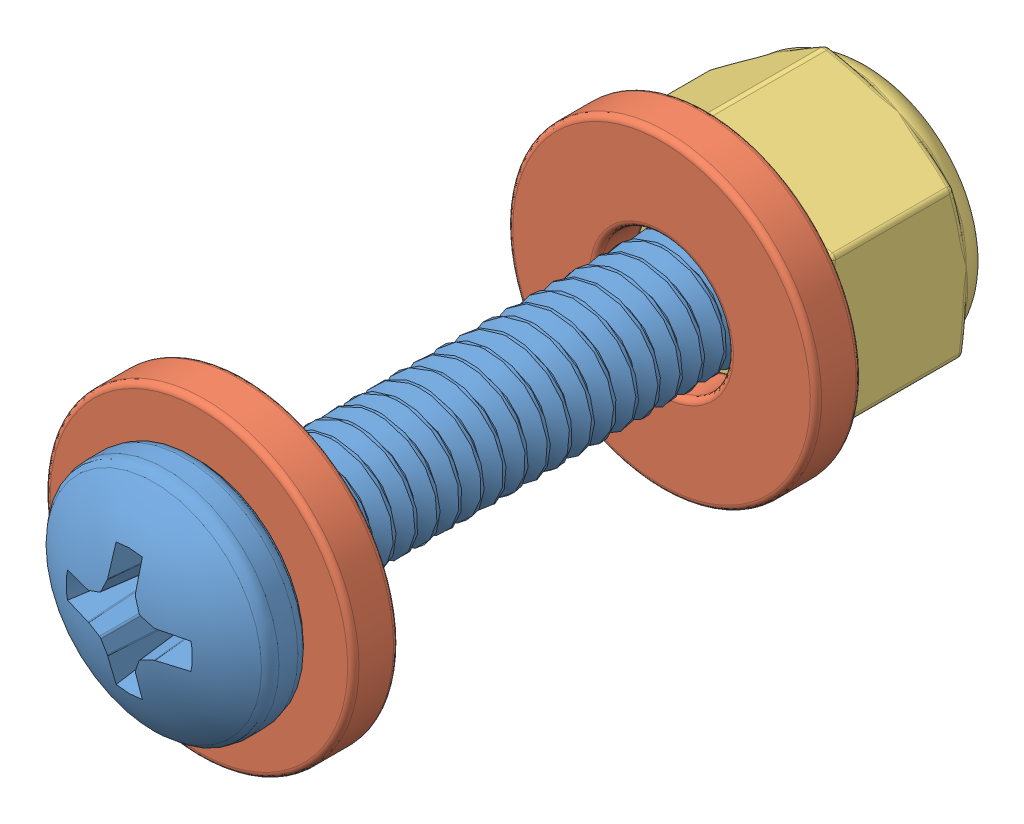
SolidWorks assembly Screwset_1_593368a, configuration  . Lengths in mm.
Overall size (13.25 12.93 28.67).
4 component instances, 3 part files, 5 mates.
Components (placement in the parent):
- 91772A199_18-8 SS PAN HEAD PHILLIPS MACHINE SCREW-1: 91772A199_18-8 SS PAN HEAD PHILLIPS MACHINE SCREW [91772A199] at origin size (8.18 8.18 28.67)
- 98023A113_ZINC YELLOW-CHROMATE PLATED STEEL FLAT WASHER-1: 98023A113_ZINC YELLOW-CHROMATE PLATED STEEL FLAT WASHER [98023A113] at (0 0 23.749) x (0.995115 -0.098725 0) z (-0.098725 -0.995115 0) size (11.11 1.65 11.11)
- 98023A113_ZINC YELLOW-CHROMATE PLATED STEEL FLAT WASHER-2: 98023A113_ZINC YELLOW-CHROMATE PLATED STEEL FLAT WASHER [98023A113] at (0 0 7.0951) x (0.999997 -0.002267 0) z (-0.002267 -0.999997 0) size (11.11 1.65 11.11)
- 90631A009_LOW-STRENGTH STEEL NYLON-INSERT LOCKNUT-1: 90631A009_LOW-STRENGTH STEEL NYLON-INSERT LOCKNUT [90631A009] at (0 0 7.0951) x (0.561011 -0.827809 0) z (0.827809 0.561011 0) size (8.84 5.95 10.02)
Mates (geometry in assembly coordinates):
- Concentric1: concentric aligned: cylinder of 91772A199_18-8 SS PAN HEAD PHILLIPS MACHINE SCREW-1 through (0 0 0) axis (0 0 1) radius 2.0828; cylinder of 98023A113_ZINC YELLOW-CHROMATE PLATED STEEL FLAT WASHER-1 through (0 0 23.749) axis (0 0 1) radius 2.3813
- Coincident1: coincident anti-aligned: plane of 91772A199_18-8 SS PAN HEAD PHILLIPS MACHINE SCREW-1 through (0 0 25.4) normal (0 0 -1); plane of 98023A113_ZINC YELLOW-CHROMATE PLATED STEEL FLAT WASHER-1 through (0 0 25.4) normal (0 0 1)
- Concentric2: concentric aligned: cylinder of 91772A199_18-8 SS PAN HEAD PHILLIPS MACHINE SCREW-1 through (0 0 0) axis (0 0 1) radius 2.0828; cylinder of 98023A113_ZINC YELLOW-CHROMATE PLATED STEEL FLAT WASHER-2 through (0 0 7.0951) axis (0 0 1) radius 2.3813
- Concentric4: concentric aligned: cylinder of 91772A199_18-8 SS PAN HEAD PHILLIPS MACHINE SCREW-1 through (0 0 0) axis (0 0 1) radius 2.0828; cylinder of 90631A009_LOW-STRENGTH STEEL NYLON-INSERT LOCKNUT-1 through (0 0 9.1779) axis (0 0 1) radius 2.0828
- Coincident2: coincident anti-aligned: plane of 98023A113_ZINC YELLOW-CHROMATE PLATED STEEL FLAT WASHER-2 through (0 0 7.0951) normal (0 0 -1); plane of 90631A009_LOW-STRENGTH STEEL NYLON-INSERT LOCKNUT-1 through (-8.7086 -0.6282 7.0951) normal (0 0 1)
